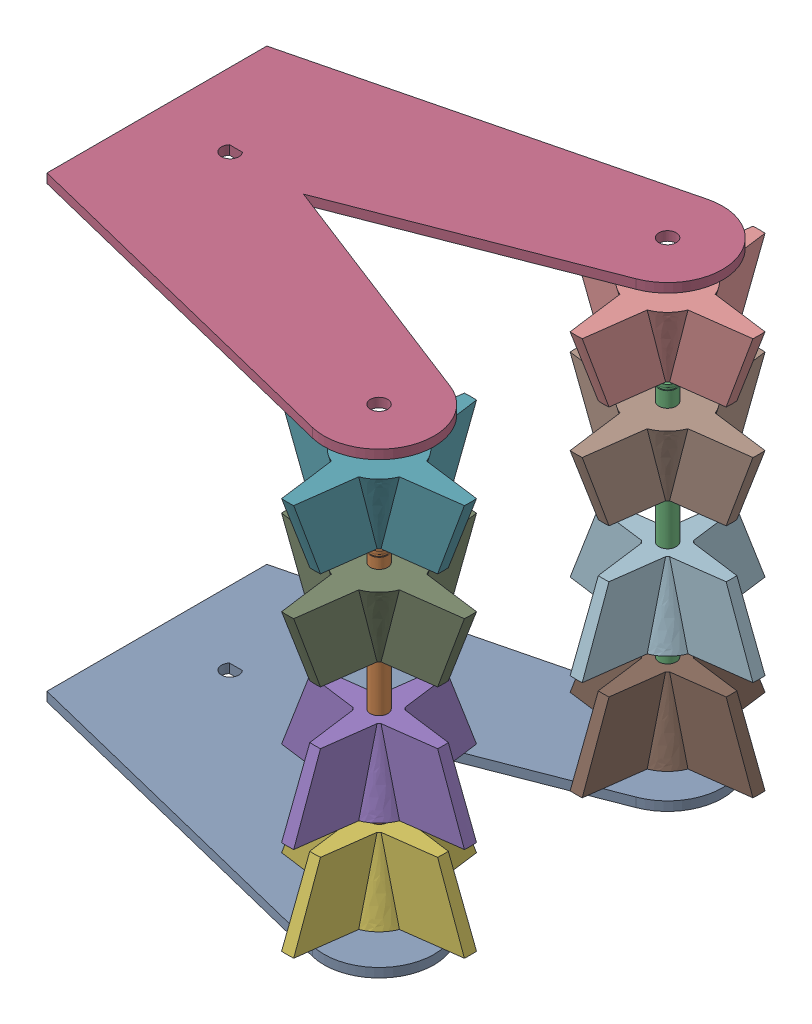
SolidWorks assembly wideIntake, configuration Default. Lengths in mm.
Overall size (158.77 158.75 163.55).
12 component instances, 3 part files, 15 mates.
Components (placement in the parent):
- intakeSidePannel-1: intakeSidePannel [Default] at (5.0223 29.747 68.0429) size (146.05 3.17 138.1)
- 6mmDShaft_4.6in-1: 6mmDShaft_4.6in [Default] at (106.6223 86.5795 118.0429) size (6 116.84 5)
- 6mmDShaft_4.6in-2: 6mmDShaft_4.6in [Default] at (106.6223 86.5795 18.0429) size (6 116.84 5)
- intakeSidePannel-2: intakeSidePannel [Default] at (5.0223 185.322 68.0429) size (146.05 3.17 138.1)
- fourPointIntakeWheel-1: fourPointIntakeWheel [Default] at (106.6223 70.1497 118.0429) size (63.55 25.4 63.55)
- fourPointIntakeWheel-2: fourPointIntakeWheel [Default] at (106.6223 37.5249 118.0429) size (63.55 25.4 63.55)
- fourPointIntakeWheel-3: fourPointIntakeWheel [Default] at (106.6223 173.4029 118.0429) x (-1 0 0) z (0 0 1) size (63.55 25.4 63.55)
- fourPointIntakeWheel-4: fourPointIntakeWheel [Default] at (106.6223 137.8286 18.0429) x (1 0 0) z (0 0 -1) size (63.55 25.4 63.55)
- fourPointIntakeWheel-5: fourPointIntakeWheel [Default] at (106.6223 139.4633 118.0429) x (1 0 0) z (0 0 -1) size (63.55 25.4 63.55)
- fourPointIntakeWheel-6: fourPointIntakeWheel [Default] at (106.6223 173.4797 18.0429) x (-1 0 0) z (0 0 1) size (63.55 25.4 63.55)
- fourPointIntakeWheel-7: fourPointIntakeWheel [Default] at (106.6223 35.676 18.0429) size (63.55 25.4 63.55)
- fourPointIntakeWheel-8: fourPointIntakeWheel [Default] at (106.6223 70.254 18.0429) size (63.55 25.4 63.55)
Mates (geometry in assembly coordinates):
- Concentric1: concentric aligned: cylinder of intakeSidePannel-1 through (106.6223 31.3345 18.0429) axis (0 -1 0) radius 3; cylinder of 6mmDShaft_4.6in-2 through (106.6223 144.9995 18.0429) axis (0 -1 0) radius 3
- Concentric2: concentric aligned: cylinder of intakeSidePannel-1 through (106.6223 31.3345 118.0429) axis (0 -1 0) radius 3; cylinder of 6mmDShaft_4.6in-1 through (106.6223 144.9995 118.0429) axis (0 -1 0) radius 3
- Concentric3: concentric aligned: cylinder of 6mmDShaft_4.6in-2 through (106.6223 144.9995 18.0429) axis (0 -1 0) radius 3; cylinder of intakeSidePannel-2 through (106.6223 186.9095 18.0429) axis (0 -1 0) radius 3
- Concentric4: concentric aligned: cylinder of 6mmDShaft_4.6in-1 through (106.6223 144.9995 118.0429) axis (0 -1 0) radius 3; cylinder of intakeSidePannel-2 through (106.6223 186.9095 118.0429) axis (0 -1 0) radius 3
- Distance1: distance = 152.4 mm anti-aligned: plane of intakeSidePannel-1 through (106.6223 31.3345 118.0429) normal (0 1 0); plane of intakeSidePannel-2 through (106.6223 183.7345 118.0429) normal (0 -1 0)
- Coincident2: coincident aligned: plane of intakeSidePannel-1 through (106.6223 28.1595 118.0429) normal (0 -1 0); plane of 6mmDShaft_4.6in-2 through (106.6223 28.1595 18.0429) normal (0 -1 0)
- Coincident3: coincident aligned: plane of intakeSidePannel-1 through (106.6223 28.1595 118.0429) normal (0 -1 0); plane of 6mmDShaft_4.6in-1 through (106.6223 28.1595 118.0429) normal (0 -1 0)
- Concentric5: concentric anti-aligned: cylinder of 6mmDShaft_4.6in-1 through (106.6223 144.9995 118.0429) axis (0 -1 0) radius 3; cylinder of fourPointIntakeWheel-1 through (106.6223 70.1496 118.0429) axis (0 1 0) radius 3
- Concentric6: concentric aligned: cylinder of 6mmDShaft_4.6in-2 through (106.6223 144.9995 18.0429) axis (0 -1 0) radius 3; circle of fourPointIntakeWheel-8
- Concentric7: concentric anti-aligned: cylinder of 6mmDShaft_4.6in-2 through (106.6223 144.9995 18.0429) axis (0 -1 0) radius 3; cylinder of fourPointIntakeWheel-7 through (106.6223 35.6759 18.0429) axis (0 1 0) radius 3
- Coincident5: coincident aligned: cylinder of 6mmDShaft_4.6in-1 through (106.6223 144.9995 118.0429) axis (0 -1 0) radius 3; circle of fourPointIntakeWheel-3
- Concentric8: concentric aligned: cylinder of 6mmDShaft_4.6in-2 through (106.6223 144.9995 18.0429) axis (0 -1 0) radius 3; circle of fourPointIntakeWheel-6
- Coincident7: coincident aligned: cylinder of 6mmDShaft_4.6in-1 through (106.6223 144.9995 118.0429) axis (0 -1 0) radius 3; circle of fourPointIntakeWheel-5
- Concentric9: concentric aligned: cylinder of 6mmDShaft_4.6in-2 through (106.6223 144.9995 18.0429) axis (0 -1 0) radius 3; cylinder of fourPointIntakeWheel-4 through (106.6223 137.8287 18.0429) axis (0 -1 0) radius 3
- Concentric10: concentric anti-aligned: cylinder of 6mmDShaft_4.6in-1 through (106.6223 144.9995 118.0429) axis (0 -1 0) radius 3; cylinder of fourPointIntakeWheel-2 through (106.6223 37.5248 118.0429) axis (0 1 0) radius 3
